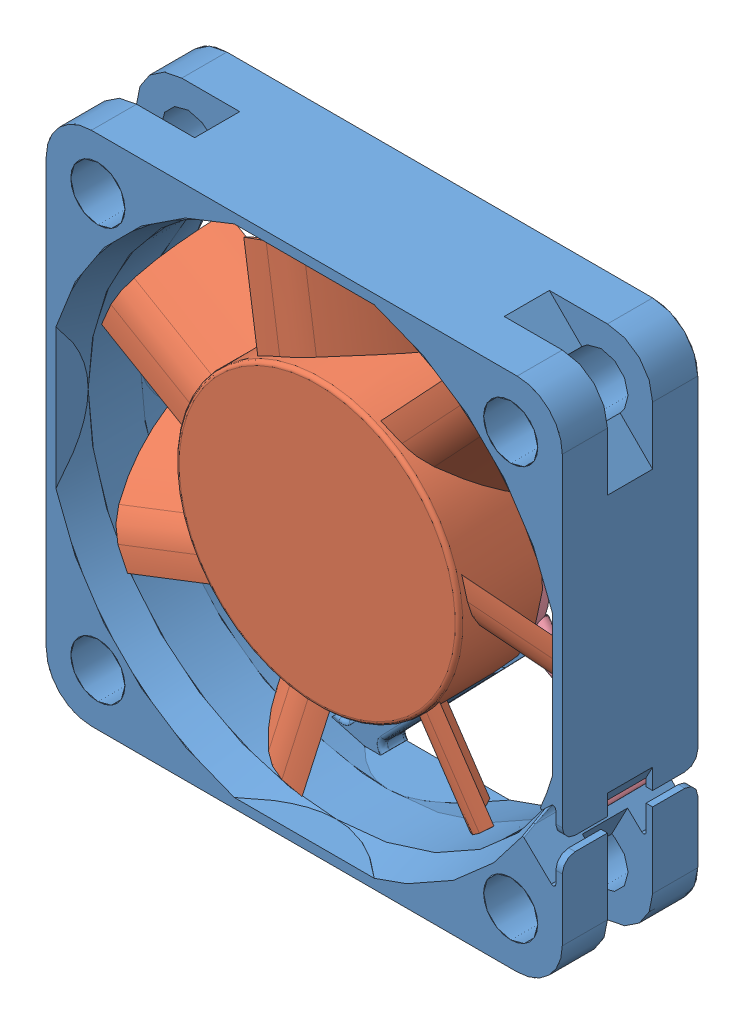
SolidWorks assembly Cooler 40x40x10 SBORKA, configuration Default. Lengths in mm.
Overall size (43.67 40 10.57).
5 component instances, 5 part files, 8 mates.
Components (placement in the parent):
- Cooler 40x40x10 body-1: Cooler 40x40x10 body [Default] at (29.9615 22.174 11.8964) size (40 40 10.5)
- Cooler Blades-1: Cooler Blades [Default] at (29.9615 22.174 14.8964) x (0.079489 0.996836 0) z (0 0 1) size (36.5 36.5 8.5)
- Cooler Motor-1: Cooler Motor [Default] at (29.9615 22.174 11.8964) size (18 18 8.5)
- Cooler pcb-1: Cooler pcb [Default] at (29.9615 22.174 14.8964) x (-0.878553 0.477645 0) z (0 0 -1) size (31.84 21.5 5.61)
- Sticker SUNON-1: Sticker SUNON [Default] at (29.9615 22.174 11.8964) x (-0.001413 -0.999999 0) z (0 0 -1) size (18 18 0.07)
Mates (geometry in assembly coordinates):
- Совпадение2: coincident anti-aligned: plane of Cooler 40x40x10 body-1 through (29.9615 22.174 13.8964) normal (0 0 1); plane of Cooler pcb-1 through (29.9615 22.174 13.8964) normal (0 0 -1)
- Концентричный1: concentric aligned: cylinder of Cooler 40x40x10 body-1 through (29.9615 22.174 22.3964) axis (0 0 -1) radius 2.75; cylinder of Cooler pcb-1 through (29.9615 22.174 14.8964) axis (0 0 -1) radius 3
- Концентричный2: concentric aligned: cylinder of Cooler 40x40x10 body-1 through (29.9615 22.174 22.3964) axis (0 0 -1) radius 2.75; cylinder of Cooler Motor-1 through (29.9615 22.174 14.8964) axis (0 0 -1) radius 2.75
- Совпадение4: coincident aligned: plane of Cooler 40x40x10 body-1 through (46.4615 38.674 11.8964) normal (0 0 -1); plane of Cooler Motor-1 through (29.9615 22.174 11.8964) normal (0 0 -1)
- Совпадение6: coincident anti-aligned: plane of Cooler 40x40x10 body-1 through (46.4615 38.674 11.8964) normal (0 0 -1); plane of Sticker SUNON-1 through (29.9615 22.174 11.8964) normal (0 0 1)
- Концентричный3: concentric anti-aligned: cylinder of Cooler 40x40x10 body-1 through (29.9615 22.174 13.8964) axis (0 0 -1) radius 11; cylinder of Sticker SUNON-1 through (29.9615 22.174 11.8464) axis (0 0 1) radius 9
- Концентричный4: concentric aligned: cylinder of Cooler Blades-1 through (29.9615 22.174 12.8964) axis (0 0 1) radius 0.7; cylinder of Cooler Motor-1 through (29.9615 22.174 12.8964) axis (0 0 1) radius 0.75
- Расстояние3: distance = 1 mm aligned: plane of Cooler Blades-1 through (29.9615 22.174 21.3964) normal (0 0 1); plane of Cooler 40x40x10 body-1 through (46.4615 38.674 22.3964) normal (0 0 1)
